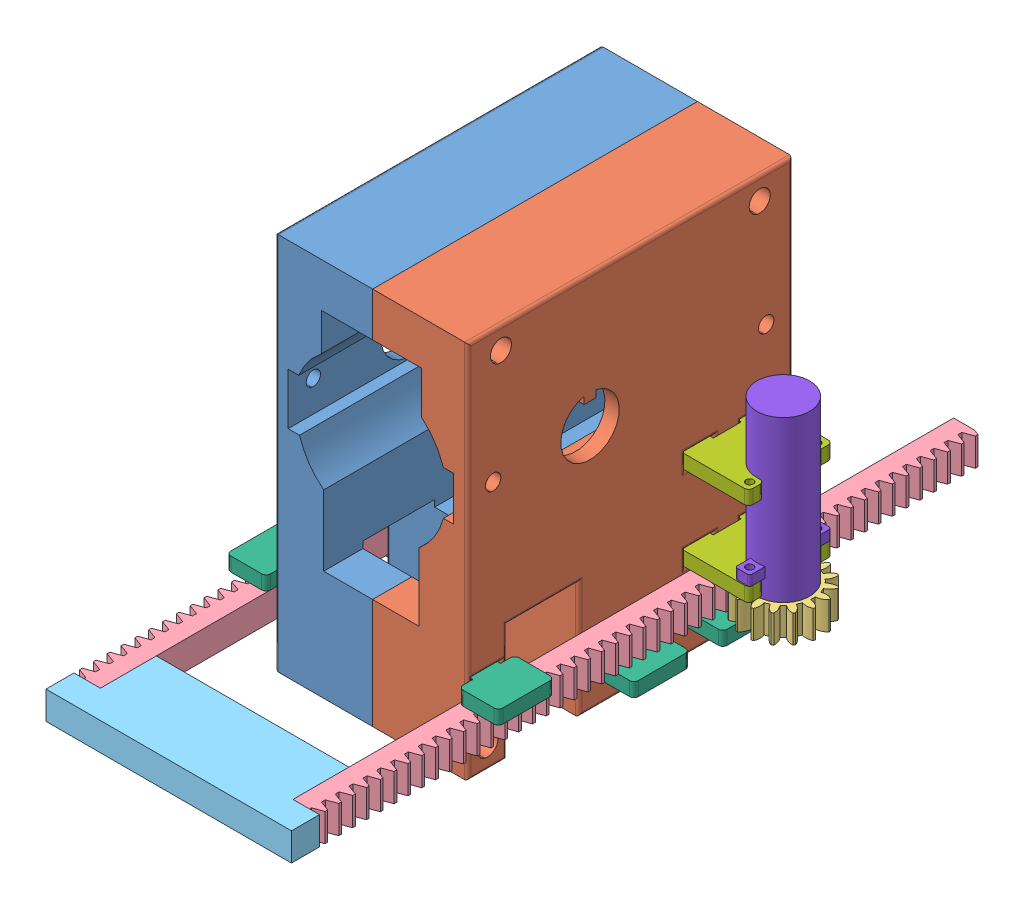
SolidWorks assembly MotorMount, configuration Default. Lengths in mm.
Overall size (89.86 86.04 156.35).
19 component instances, 8 part files, 50 mates.
Components (placement in the parent):
- MarkerCage_Left_v4_1-1: MarkerCage_Left_v4_1 [Default] at (18.2599 65.3641 30.583) size (22.11 86.04 73.76)
- MarkerCage_Right_v4_1-1: MarkerCage_Right_v4_1 [Default] at (34.9619 69.7973 30.583) size (21.63 86.04 73.76)
- spur gear_am-1: spur gear_am [Metric - Spur gear 1M 16T 20PA 6.35FW ---S16N75H50L1N] at (62.8798 21.1693 45.458) x (0 1 0) z (0 0 1) size (6.35 17.74 17.74)
- spur gear_am-2: spur gear_am [Metric - Spur gear 1M 16T 20PA 6.35FW ---S16N75H50L1N] at (-6.3175 21.1693 45.458) x (0 1 0) z (0.90602 0 0.423236) size (6.35 17.74 17.74)
- rack spur rectangular_am-1: rack spur rectangular_am [Metric - Rack-spur - rectangular 1M 20PA 6.35FW 5PH 150L---SAll] at (50.1511 21.1693 144.0513) x (0 0 -1) z (0 -1 0) size (150 6 6.35)
- rack spur rectangular_am-2: rack spur rectangular_am [Metric - Rack-spur - rectangular 1M 20PA 6.35FW 5PH 150L---SAll] at (6.4111 27.5193 144.0513) x (0 0 -1) z (0 1 0) size (150 6 6.35)
- triggerbar_v4_1-1: triggerbar_v4_1 [Default] at (6.4111 27.5193 131.3513) x (1 0 0) z (0 0 -1) size (55.74 6.35 19.05)
- rackguard_v4_1-1: rackguard_v4_1 [Default] at (12.7611 20.6943 66.113) x (0 0 1) z (1 0 0) size (12.7 3.17 15.35)
- rackguard_v4_1-2: rackguard_v4_1 [Default] at (12.7611 20.6943 45.933) x (0 0 1) z (1 0 0) size (12.7 3.17 15.35)
- rackguard_v4_1-3: rackguard_v4_1 [Default] at (12.7611 30.6943 96.898) x (0 0 1) z (1 0 0) size (12.7 3.17 15.35)
- rackguard_v4_1-4: rackguard_v4_1 [Default] at (43.8011 20.6943 52.283) x (0 0 -1) z (-1 0 0) size (12.7 3.17 15.35)
- rackguard_v4_1-5: rackguard_v4_1 [Default] at (43.8011 30.6943 103.248) x (0 0 -1) z (-1 0 0) size (12.7 3.17 15.35)
- rackguard_v4_1-6: rackguard_v4_1 [Default] at (43.8011 20.6943 72.463) x (0 0 -1) z (-1 0 0) size (12.7 3.17 15.35)
- motormount_v4_1-1: motormount_v4_1 [Default] at (6.4111 31.8093 35.933) x (0 0 1) z (1 0 0) size (19.05 3.17 20.74)
- motormount_v4_1-2: motormount_v4_1 [Default] at (6.4111 50.8593 35.933) x (0 0 1) z (1 0 0) size (19.05 3.17 20.74)
- motormount_v4_1-3: motormount_v4_1 [Default] at (50.1511 31.8093 54.983) x (0 0 -1) z (-1 0 0) size (19.05 3.17 20.74)
- motormount_v4_1-4: motormount_v4_1 [Default] at (50.1511 50.8593 54.983) x (0 0 -1) z (-1 0 0) size (19.05 3.17 20.74)
- VigorMotor_v0-1: VigorMotor_v0 [Default] at (-6.3175 34.0993 45.458) x (0 0 -1) z (-1 0 0) size (18.57 40.41 12)
- VigorMotor_v0-2: VigorMotor_v0 [Default] at (62.8798 34.0993 45.458) x (0 0 -1) z (-1 0 0) size (18.57 40.41 12)
Mates (geometry in assembly coordinates):
- Coincident1: coincident aligned: plane of MarkerCage_Left_v4_1-1 through (6.4111 97.2093 104.343) normal (0 1 0); plane of MarkerCage_Right_v4_1-1 through (28.5211 97.2093 104.343) normal (0 1 0)
- Coincident2: coincident aligned: plane of MarkerCage_Left_v4_1-1 through (27.4564 64.9565 104.343) normal (0 0 1); plane of MarkerCage_Right_v4_1-1 through (29.1206 65.1512 104.343) normal (0 0 1)
- Coincident3: coincident anti-aligned: plane of MarkerCage_Left_v4_1-1 through (28.5211 87.2093 104.343) normal (1 0 0); plane of MarkerCage_Right_v4_1-1 through (28.5211 87.2093 104.343) normal (-1 0 0)
- Coincident57: coincident aligned: plane of rack spur rectangular_am-1 through (50.1511 27.5193 144.0513) normal (0 0 1); plane of rack spur rectangular_am-2 through (6.4111 21.1693 144.0513) normal (0 0 1)
- Coincident69: coincident anti-aligned: plane of rack spur rectangular_am-1 through (50.1511 27.5193 144.0513) normal (0 0 1); plane of triggerbar_v4_1-1 through (50.1511 21.1693 144.0513) normal (0 0 -1)
- Coincident71: coincident aligned: plane of rack spur rectangular_am-2 through (0.4111 27.5193 144.0513) normal (0 1 0); plane of triggerbar_v4_1-1 through (6.4111 27.5193 131.3513) normal (0 1 0)
- Coincident72: coincident anti-aligned: plane of MarkerCage_Left_v4_1-1 through (6.4111 11.1693 104.343) normal (-1 0 0); plane of rack spur rectangular_am-2 through (6.4111 21.1693 144.0513) normal (1 0 0)
- Coincident73: coincident anti-aligned: plane of MarkerCage_Right_v4_1-1 through (50.1511 11.1693 104.343) normal (1 0 0); plane of rack spur rectangular_am-1 through (50.1511 27.5193 144.0513) normal (-1 0 0)
- Coincident74: coincident anti-aligned: plane of MarkerCage_Left_v4_1-1 through (28.5211 17.5193 65.763) normal (0 1 0); plane of rackguard_v4_1-1 through (12.7611 17.5193 66.113) normal (0 -1 0)
- Coincident76: coincident anti-aligned: plane of MarkerCage_Left_v4_1-1 through (28.5211 21.0193 72.463) normal (0 0 -1); plane of rackguard_v4_1-1 through (12.7611 17.5193 72.463) normal (0 0 1)
- Coincident77: coincident anti-aligned: plane of MarkerCage_Left_v4_1-1 through (6.4111 11.1693 104.343) normal (-1 0 0); plane of rackguard_v4_1-1 through (6.4111 17.5193 72.463) normal (1 0 0)
- Coincident78: coincident anti-aligned: plane of MarkerCage_Left_v4_1-1 through (28.5211 17.5193 45.583) normal (0 1 0); plane of rackguard_v4_1-2 through (12.7611 17.5193 45.933) normal (0 -1 0)
- Coincident79: coincident anti-aligned: plane of MarkerCage_Left_v4_1-1 through (28.5211 21.0193 52.283) normal (0 0 -1); plane of rackguard_v4_1-2 through (12.7611 17.5193 52.283) normal (0 0 1)
- Coincident80: coincident anti-aligned: plane of MarkerCage_Left_v4_1-1 through (6.4111 11.1693 104.343) normal (-1 0 0); plane of rackguard_v4_1-2 through (6.4111 17.5193 42.758) normal (1 0 0)
- Coincident81: coincident anti-aligned: plane of MarkerCage_Left_v4_1-1 through (28.5211 27.5193 96.548) normal (0 1 0); plane of rackguard_v4_1-3 through (12.7611 27.5193 96.898) normal (0 -1 0)
- Coincident82: coincident anti-aligned: plane of MarkerCage_Left_v4_1-1 through (28.5211 31.0193 103.248) normal (0 0 -1); plane of rackguard_v4_1-3 through (12.7611 27.5193 103.248) normal (0 0 1)
- Coincident83: coincident anti-aligned: plane of MarkerCage_Left_v4_1-1 through (6.4111 11.1693 104.343) normal (-1 0 0); plane of rackguard_v4_1-3 through (6.4111 27.5193 93.723) normal (1 0 0)
- Coincident84: coincident anti-aligned: plane of rack spur rectangular_am-2 through (0.4111 27.5193 144.0513) normal (0 1 0); plane of rackguard_v4_1-3 through (12.7611 27.5193 96.898) normal (0 -1 0)
- Coincident85: coincident anti-aligned: plane of MarkerCage_Right_v4_1-1 through (28.5211 27.5193 103.248) normal (0 1 0); plane of rackguard_v4_1-5 through (43.8011 27.5193 103.248) normal (0 -1 0)
- Coincident86: coincident anti-aligned: plane of MarkerCage_Right_v4_1-1 through (28.5211 31.0193 103.248) normal (0 0 -1); plane of rackguard_v4_1-5 through (43.8011 27.5193 103.248) normal (0 0 1)
- Coincident87: coincident anti-aligned: plane of MarkerCage_Right_v4_1-1 through (50.1511 11.1693 104.343) normal (1 0 0); plane of rackguard_v4_1-5 through (50.1511 27.5193 106.423) normal (-1 0 0)
- Coincident88: coincident anti-aligned: plane of MarkerCage_Right_v4_1-1 through (28.5211 17.5193 72.463) normal (0 1 0); plane of rackguard_v4_1-6 through (43.8011 17.5193 72.463) normal (0 -1 0)
- Coincident89: coincident anti-aligned: plane of MarkerCage_Right_v4_1-1 through (28.5211 21.0193 72.463) normal (0 0 -1); plane of rackguard_v4_1-6 through (43.8011 17.5193 72.463) normal (0 0 1)
- Coincident90: coincident anti-aligned: plane of MarkerCage_Right_v4_1-1 through (50.1511 11.1693 104.343) normal (1 0 0); plane of rackguard_v4_1-6 through (50.1511 17.5193 66.113) normal (-1 0 0)
- Coincident91: coincident anti-aligned: plane of MarkerCage_Right_v4_1-1 through (28.5211 17.5193 52.283) normal (0 1 0); plane of rackguard_v4_1-4 through (43.8011 17.5193 52.283) normal (0 -1 0)
- Coincident92: coincident anti-aligned: plane of MarkerCage_Right_v4_1-1 through (28.5211 21.0193 52.283) normal (0 0 -1); plane of rackguard_v4_1-4 through (43.8011 17.5193 52.283) normal (0 0 1)
- Coincident93: coincident anti-aligned: plane of MarkerCage_Right_v4_1-1 through (50.1511 11.1693 104.343) normal (1 0 0); plane of rackguard_v4_1-4 through (50.1511 17.5193 45.933) normal (-1 0 0)
- Coincident94: coincident anti-aligned: plane of rack spur rectangular_am-1 through (56.1511 27.5193 144.0513) normal (0 1 0); plane of rackguard_v4_1-5 through (43.8011 27.5193 103.248) normal (0 -1 0)
- Coincident95: coincident anti-aligned: plane of MarkerCage_Left_v4_1-1 through (28.5211 28.6343 35.583) normal (0 1 0); plane of motormount_v4_1-1 through (6.4111 28.6343 35.933) normal (0 -1 0)
- Coincident96: coincident anti-aligned: plane of MarkerCage_Left_v4_1-1 through (28.5211 32.1343 42.283) normal (0 0 -1); plane of motormount_v4_1-1 through (6.4111 28.6343 42.283) normal (0 0 1)
- Coincident97: coincident anti-aligned: plane of MarkerCage_Left_v4_1-1 through (6.4111 11.1693 104.343) normal (-1 0 0); plane of motormount_v4_1-1 through (6.4111 28.6343 35.933) normal (1 0 0)
- Coincident98: coincident anti-aligned: plane of MarkerCage_Left_v4_1-1 through (28.5211 47.6843 35.583) normal (0 1 0); plane of motormount_v4_1-2 through (6.4111 47.6843 35.933) normal (0 -1 0)
- Coincident99: coincident anti-aligned: plane of MarkerCage_Left_v4_1-1 through (28.5211 51.1843 42.283) normal (0 0 -1); plane of motormount_v4_1-2 through (6.4111 47.6843 42.283) normal (0 0 1)
- Coincident100: coincident anti-aligned: plane of MarkerCage_Left_v4_1-1 through (6.4111 11.1693 104.343) normal (-1 0 0); plane of motormount_v4_1-2 through (6.4111 47.6843 35.933) normal (1 0 0)
- Coincident101: coincident anti-aligned: plane of motormount_v4_1-1 through (6.4111 31.8093 35.933) normal (0 1 0); plane of VigorMotor_v0-1 through (-6.3175 31.8093 45.458) normal (0 -1 0)
- Concentric1: concentric aligned: cylinder of motormount_v4_1-1 through (-6.3175 28.6343 37.8155) axis (0 1 0) radius 0.845; cylinder of VigorMotor_v0-1 through (-6.3175 31.8093 37.8155) axis (0 1 0) radius 0.845
- Concentric2: concentric aligned: cylinder of motormount_v4_1-1 through (-6.3175 28.6343 53.1005) axis (0 1 0) radius 0.845; cylinder of VigorMotor_v0-1 through (-6.3175 31.8093 53.1005) axis (0 1 0) radius 0.845
- Coincident102: coincident anti-aligned: plane of spur gear_am-2 through (-6.3175 27.5193 45.458) normal (0 1 0); plane of VigorMotor_v0-1 through (-6.3175 27.5193 45.458) normal (0 -1 0)
- Concentric3: concentric anti-aligned: cylinder of spur gear_am-2 through (-6.3175 71.1694 45.458) axis (0 -1 0) radius 0.5; cylinder of VigorMotor_v0-1 through (-6.3175 23.4794 45.458) axis (0 1 0) radius 2.205
- Coincident103: coincident anti-aligned: plane of MarkerCage_Right_v4_1-1 through (28.5211 28.6343 35.583) normal (0 1 0); plane of motormount_v4_1-3 through (50.1511 28.6343 54.983) normal (0 -1 0)
- Coincident104: coincident anti-aligned: plane of MarkerCage_Right_v4_1-1 through (28.5211 28.6343 54.983) normal (0 0 -1); plane of motormount_v4_1-3 through (50.1511 28.6343 54.983) normal (0 0 1)
- Coincident105: coincident anti-aligned: plane of MarkerCage_Right_v4_1-1 through (50.1511 11.1693 104.343) normal (1 0 0); plane of motormount_v4_1-3 through (50.1511 28.6343 54.983) normal (-1 0 0)
- Coincident106: coincident anti-aligned: plane of MarkerCage_Right_v4_1-1 through (28.5211 47.6843 35.583) normal (0 1 0); plane of motormount_v4_1-4 through (50.1511 47.6843 54.983) normal (0 -1 0)
- Coincident107: coincident anti-aligned: plane of MarkerCage_Right_v4_1-1 through (28.5211 47.6843 54.983) normal (0 0 -1); plane of motormount_v4_1-4 through (50.1511 47.6843 54.983) normal (0 0 1)
- Coincident108: coincident anti-aligned: plane of MarkerCage_Right_v4_1-1 through (50.1511 11.1693 104.343) normal (1 0 0); plane of motormount_v4_1-4 through (50.1511 47.6843 54.983) normal (-1 0 0)
- Concentric4: concentric anti-aligned: cylinder of motormount_v4_1-4 through (62.8798 47.6843 45.458) axis (0 1 0) radius 6; cylinder of VigorMotor_v0-2 through (62.8798 63.8893 45.458) axis (0 -1 0) radius 6
- Concentric5: concentric aligned: cylinder of motormount_v4_1-3 through (62.8798 28.6343 37.8155) axis (0 1 0) radius 0.845; cylinder of VigorMotor_v0-2 through (62.8798 31.8093 37.8155) axis (0 1 0) radius 0.845
- Coincident109: coincident anti-aligned: plane of motormount_v4_1-3 through (50.1511 31.8093 54.983) normal (0 1 0); plane of VigorMotor_v0-2 through (62.8798 31.8093 45.458) normal (0 -1 0)
- Concentric6: concentric anti-aligned: cylinder of spur gear_am-1 through (62.8798 71.1694 45.458) axis (0 -1 0) radius 0.5; cylinder of VigorMotor_v0-2 through (62.8798 23.4794 45.458) axis (0 1 0) radius 2.205
- Coincident110: coincident anti-aligned: plane of spur gear_am-1 through (62.8798 27.5193 45.458) normal (0 1 0); plane of VigorMotor_v0-2 through (62.8798 27.5193 45.458) normal (0 -1 0)
